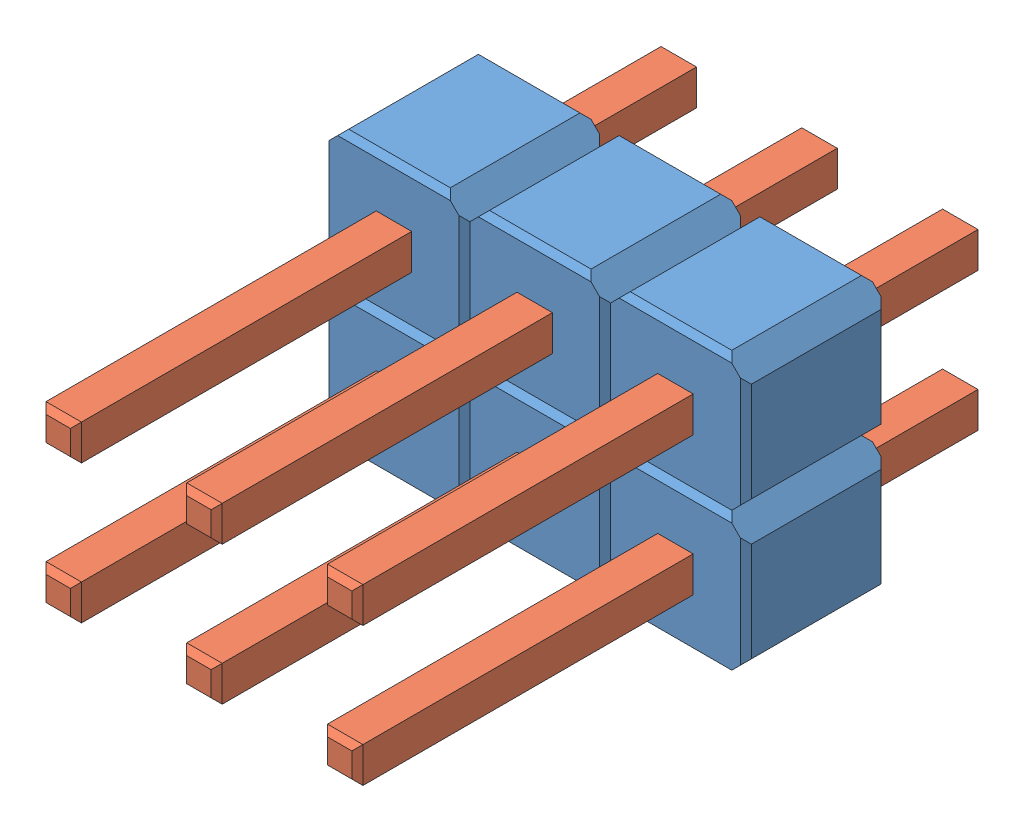
SolidWorks assembly Сборка13, configuration Default. Lengths in mm.
Overall size (7.62 5 11.3).
20 component instances, 2 part files, 2 mates.
Components (placement in the parent):
- pls_1x3_vert-1: pls_1x3_vert [Default] at (0.5332 -0.4629 1.3734) size (7.62 2.5 11.3)
  - pls_1_vert-1: pls_1_vert [Default] at (2.4589 -1.2488 -2.1291) size (2.54 2.5 11.3)
    - pin_plastic-1: pin_plastic [По умолчанию] at (1.6831 0.6372 -1.2507) size (2.54 2.5 2.54)
    - pin-1: pin [Default] at (-0.8569 0.6372 7.3493) x (1 0 0) z (0 1 0) size (0.64 11.3 0.64)
  - pls_1_vert-2: pls_1_vert [Default] at (-0.0811 -1.2488 -2.1291) size (2.54 2.5 11.3)
    - pin_plastic-1: pin_plastic [По умолчанию] at (1.6831 0.6372 -1.2507) size (2.54 2.5 2.54)
    - pin-1: pin [Default] at (-0.8569 0.6372 7.3493) x (1 0 0) z (0 1 0) size (0.64 11.3 0.64)
  - pls_1_vert-4: pls_1_vert [Default] at (-2.6211 -1.2488 -2.1291) size (2.54 2.5 11.3)
    - pin_plastic-1: pin_plastic [По умолчанию] at (1.6831 0.6372 -1.2507) size (2.54 2.5 2.54)
    - pin-1: pin [Default] at (-0.8569 0.6372 7.3493) x (1 0 0) z (0 1 0) size (0.64 11.3 0.64)
- pls_1x3_vert-2: pls_1x3_vert [Default] at (0.5332 2.0371 1.3734) size (7.62 2.5 11.3)
  - pls_1_vert-1: pls_1_vert [Default] at (2.4589 -1.2488 -2.1291) size (2.54 2.5 11.3)
    - pin_plastic-1: pin_plastic [По умолчанию] at (1.6831 0.6372 -1.2507) size (2.54 2.5 2.54)
    - pin-1: pin [Default] at (-0.8569 0.6372 7.3493) x (1 0 0) z (0 1 0) size (0.64 11.3 0.64)
  - pls_1_vert-2: pls_1_vert [Default] at (-0.0811 -1.2488 -2.1291) size (2.54 2.5 11.3)
    - pin_plastic-1: pin_plastic [По умолчанию] at (1.6831 0.6372 -1.2507) size (2.54 2.5 2.54)
    - pin-1: pin [Default] at (-0.8569 0.6372 7.3493) x (1 0 0) z (0 1 0) size (0.64 11.3 0.64)
  - pls_1_vert-4: pls_1_vert [Default] at (-2.6211 -1.2488 -2.1291) size (2.54 2.5 11.3)
    - pin_plastic-1: pin_plastic [По умолчанию] at (1.6831 0.6372 -1.2507) size (2.54 2.5 2.54)
    - pin-1: pin [Default] at (-0.8569 0.6372 7.3493) x (1 0 0) z (0 1 0) size (0.64 11.3 0.64)
Mates (geometry in assembly coordinates):
- Совпадение2: coincident aligned: line of pls_1x3_vert-1/pls_1_vert-1/pin_plastic-1 through (3.0516 0.1755 0.4336) axis (0 0 -1); line of pls_1x3_vert-2/pls_1_vert-1/pin_plastic-1 through (3.0516 0.1755 0.4336) axis (0 0 -1)
- Совпадение3: coincident anti-aligned: line of pls_1x3_vert-1/pls_1_vert-1/pin_plastic-1 through (1.2187 0.1755 0.4336) axis (1 0 0); line of pls_1x3_vert-2/pls_1_vert-1/pin_plastic-1 through (3.0516 0.1755 0.4336) axis (-1 0 0)
